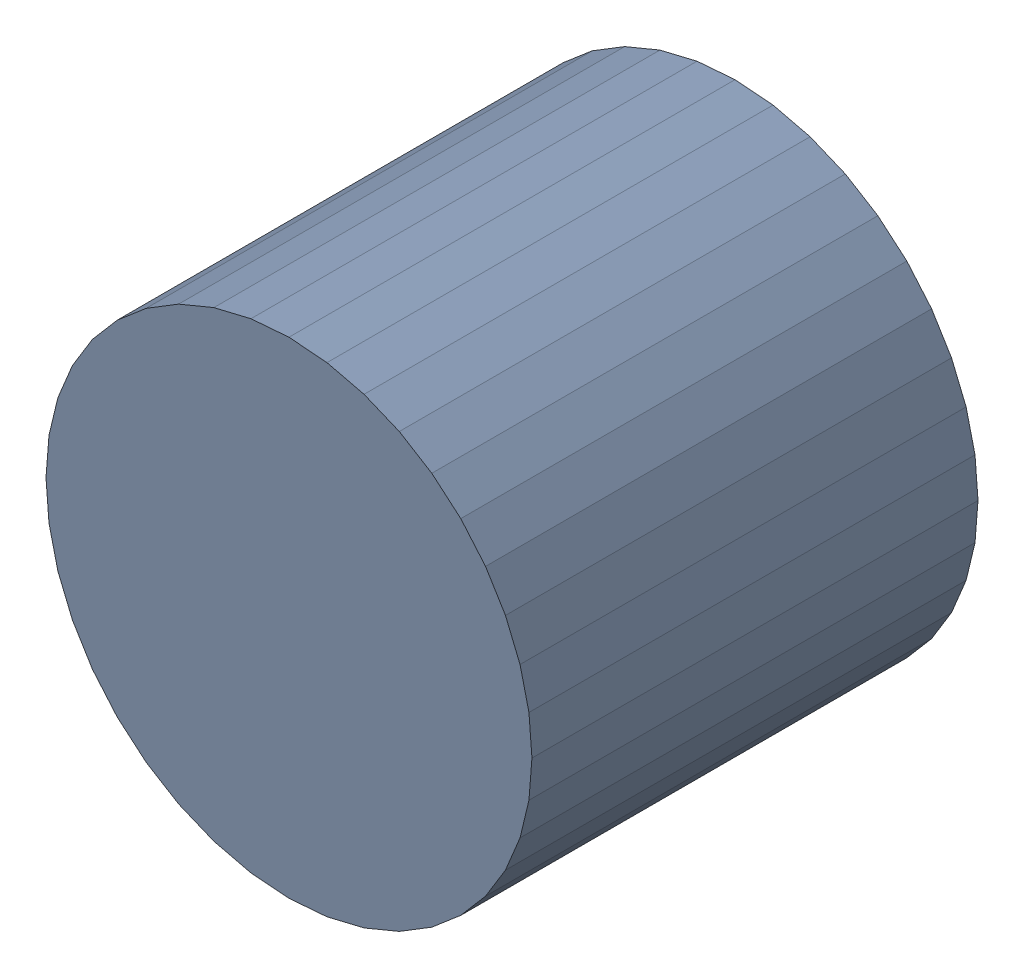
SolidWorks assembly C10_Motor_10Kanaloa_v2.0.0_Motor, configuration Default. Lengths in mm.
Overall size (6.32 6.32 5.8).
2 component instances, 1 part files, 0 mates.
Components (placement in the parent):
- 352892112-1: 352892112 [Default] at (88.9 155.194 0) size (6.32 6.32 5.8)
  - Extruded_11-1: Extruded_11 [Default] at origin size (6.32 6.32 5.8)
